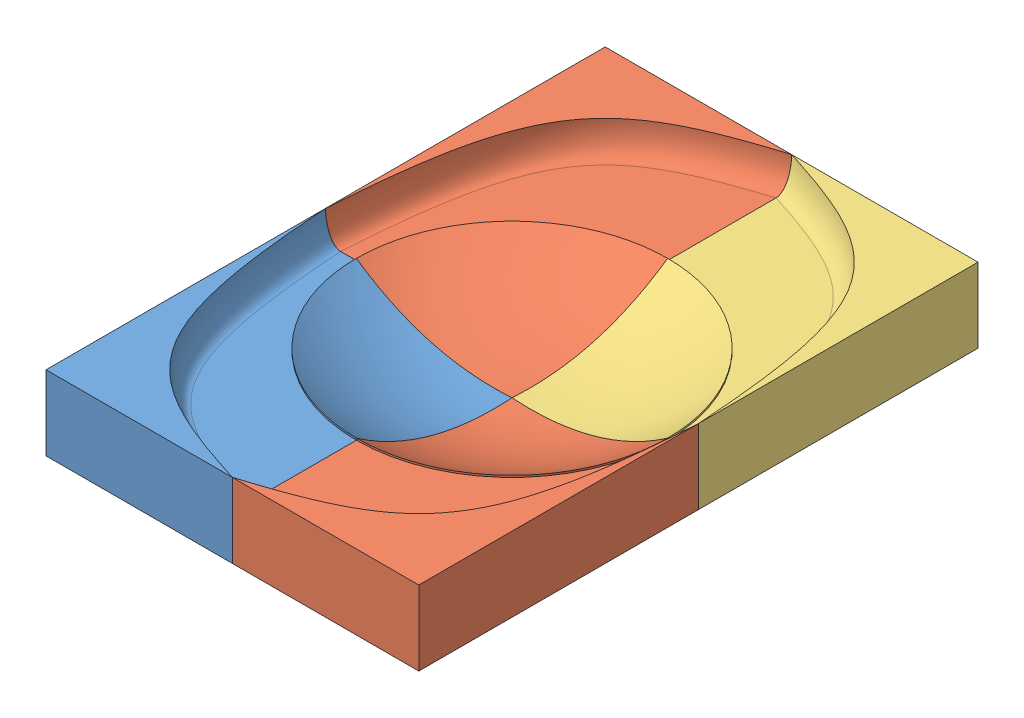
SolidWorks assembly full_transdec, configuration Default. Lengths in mm.
Overall size (62513.9 12968.95 92993.9).
4 component instances, 3 part files, 1 mates.
Components (placement in the parent):
- transdec_corner-1: transdec_corner [Default] at (-15240 12192 22860) x (-1 0 0) z (0 -1 0) size (33813.99 49053.99 12968.95)
- Mirrortransdec_corner-4: Mirrortransdec_corner [Default] at (15240 12192 22860) x (1 0 0) z (0 1 0) size (33813.99 49053.99 12968.95)
- Mirrortransdec_corner-7: Mirrortransdec_corner [Default] at (-15240 12192 -22860) x (-1 0 0) z (0 1 0) size (33813.99 49053.99 12968.95)
- MirrorMirrortransdec_corner-8: MirrorMirrortransdec_corner [Default] at (15240 12192 -22860) x (1 0 0) z (0 -1 0) size (33813.99 49053.99 12968.95)
Mates (geometry in assembly coordinates):
- Parallel1: parallel anti-aligned: plane of transdec_corner-1 through (-15240 12192 22860) normal (0 0 -1)
